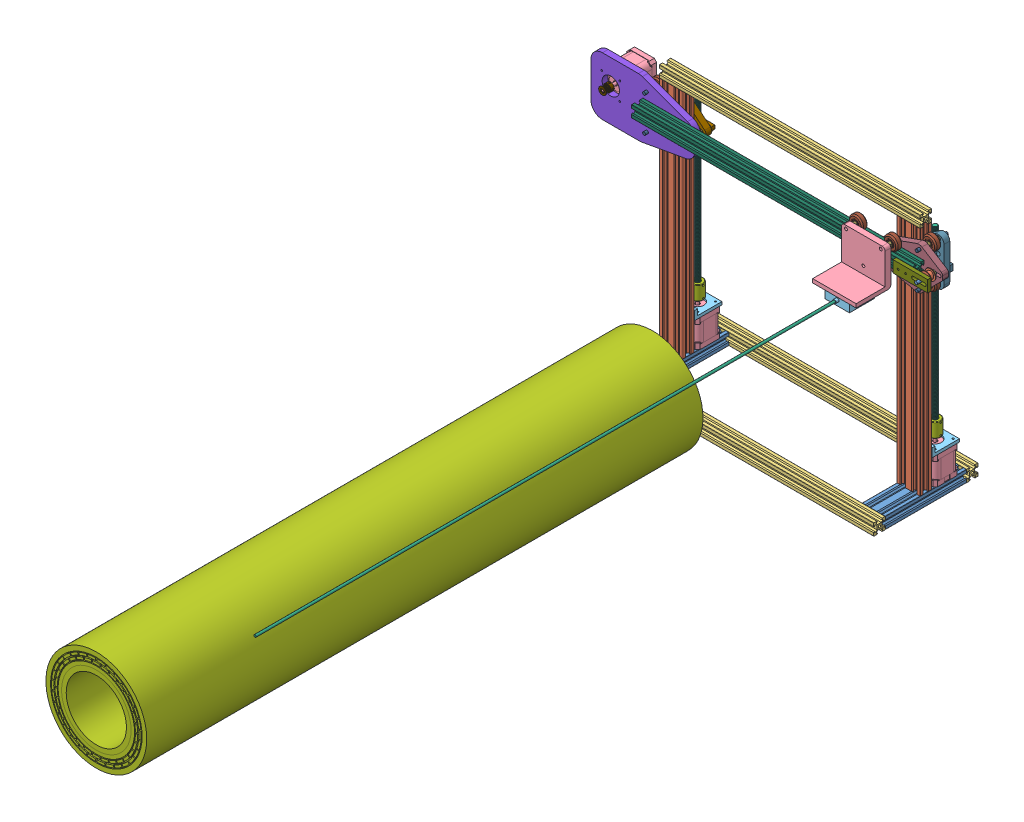
SolidWorks assembly Assembly_Design_1, configuration Default. Lengths in mm.
Overall size (607.25 440 1291.55).
72 component instances, 28 part files, 190 mates.
Components (placement in the parent):
- V_Slot_40x20_140mm-1: V_Slot_40x20_140mm [Default] at (9.5 10 -140) x (0 -1 0) z (0 0 1) size (20 40 140)
- V_Slot_40x20_400mm-1: V_Slot_40x20_400mm [Default] at (9.5 420 -70) x (0 0 -1) z (0 -1 0) size (20 40 400)
- V_Slot_20x20_450mm-1: V_Slot_20x20_450mm [Default] at (-0.5 430 -70) x (0 0 -1) z (1 0 0) size (20 20 450)
- V_Slot_40x20_400mm-2: V_Slot_40x20_400mm [Default] at (419.5 20 -70) x (0 0 1) z (0 1 0) size (20 40 400)
- V_Slot_40x20_140mm-2: V_Slot_40x20_140mm [Default] at (439.5 10 -140) x (0 1 0) z (0 0 1) size (20 40 140)
- V_Slot_20x20_450mm-2: V_Slot_20x20_450mm [Default] at (449.5 10 10) x (0 0 1) z (-1 0 0) size (20 20 450)
- V_Slot_20x20_450mm-3: V_Slot_20x20_450mm [Default] at (-0.5 10 -150) x (0 0 -1) z (1 0 0) size (20 20 450)
- Stepper_Motor_17HS19-2004S1-1: Stepper_Motor_17HS19-2004S1 [Predeterminado] at (19.5 44 -106) x (1 0 0) z (0 1 0) size (42 42 72)
- stepper_motor_mounting_bracket-1: stepper_motor_mounting_bracket [Default] at (19.5 68 -106) x (-1 0 0) z (0 1 0) size (42 47 15)
- Stepper_Motor_17HS19-2004S1-2: Stepper_Motor_17HS19-2004S1 [Predeterminado] at (429.5 44 -106) x (-1 0 0) z (0 1 0) size (42 42 72)
- stepper_motor_mounting_bracket-2: stepper_motor_mounting_bracket [Default] at (429.5 68 -106) x (-1 0 0) z (0 1 0) size (42 47 15)
- LeadScrew 8mm x 2mmPitch-1: LeadScrew 8mm x 2mmPitch [Default] at (429.5 92 -106) x (0.998698 0 -0.051019) z (0 -1 0) size (9.24 8.22 303.06)
- Coupling_Shaft_5x8-1: Coupling_Shaft_5x8 [Default] at (429.5 79.5 -106) x (0.999828 0 -0.01857) z (0.01857 0 0.999828) size (19 25 19)
- LeadScrew 8mm x 2mmPitch-2: LeadScrew 8mm x 2mmPitch [Default] at (19.5 92 -106) x (1 0 0) z (0 -1 0) size (9.24 8.22 303.06)
- Coupling_Shaft_5x8-2: Coupling_Shaft_5x8 [Default] at (19.5 79.5 -106) x (0.999319 0 -0.036886) z (0.036886 0 0.999319) size (19 25 19)
- leftbeam_wheel_mount_front-2: leftbeam_wheel_mount_front [Default] at (-107.5 320 -58.8) x (1 0 0) z (0 -1 0) size (180 10 100)
- Stepper_Motor_17HS19-2004S1-4: Stepper_Motor_17HS19-2004S1 [Predeterminado] at (-73 377.5 -82.8) size (42 42 72)
- leftbeam_wheel_mount_back-2: leftbeam_wheel_mount_back [Default] at (-21 326.9634 -91) x (1 0 0) z (0 -1 0) size (80 40 83.06)
- Wheel_mount_rod_for_brackets-1: Wheel_mount_rod_for_brackets [Default] at (-10.7 400 -96) x (-0.970108 -0.242673 0) z (-0.242673 0.970108 0) size (5 52.2 5)
- Wheel_mount_rod_for_brackets-2: Wheel_mount_rod_for_brackets [Default] at (-10.7 340 -96) x (-0.232708 0.972547 0) z (0.972547 0.232708 0) size (5 52.2 5)
- Wheel_mount_rod_for_brackets-3: Wheel_mount_rod_for_brackets [Default] at (49.8 355 -96) x (-0.732499 0.680769 0) z (0.680769 0.732499 0) size (5 52.2 5)
- V_Slot_Wheel_OD24xID5-1: V_Slot_Wheel_OD24xID5 [Default] at (-10.7 400 -69.9) x (0.993327 -0.115336 0) z (0 0 1) size (24 24 10.2)
- M5 Hex nut-1: M5 Hex nut [Default] at (-10.7 400 -61.8) x (0.939693 -0.34202 0) z (0.34202 0.939693 0) size (9.01 6.7 7.8)
- M5 Hex nut-2: M5 Hex nut [Default] at (-10.7 400 -78) x (0.939693 -0.34202 0) z (-0.34202 -0.939693 0) size (9.01 6.7 7.8)
- M5 Hex nut-3: M5 Hex nut [Default] at (-10.7 340 -61.8) x (0 -1 0) z (1 0 0) size (9.01 6.7 7.8)
- M5 Hex nut-4: M5 Hex nut [Default] at (-10.7 340 -78) x (0 -1 0) z (1 0 0) size (9.01 6.7 7.8)
- V_Slot_Wheel_OD24xID5-2: V_Slot_Wheel_OD24xID5 [Default] at (-10.7 340 -69.9) x (0.998331 -0.057756 0) z (0 0 1) size (24 24 10.2)
- M5 Hex nut-5: M5 Hex nut [Default] at (49.8 355 -78) x (0.866025 -0.5 0) z (-0.5 -0.866025 0) size (9.01 6.7 7.8)
- M5 Hex nut-6: M5 Hex nut [Default] at (49.8 355 -61.8) x (0.866025 -0.5 0) z (0.5 0.866025 0) size (9.01 6.7 7.8)
- V_Slot_Wheel_OD24xID5-3: V_Slot_Wheel_OD24xID5 [Default] at (49.8 355 -69.9) x (0.999874 0.01588 0) z (0 0 1) size (24 24 10.2)
- rightbeam_wheel_mount_front-1: rightbeam_wheel_mount_front [Default] at (499.75 372.8501 -58.8) size (110 73.04 10)
- rightbeam_wheels_mount _back-1: rightbeam_wheels_mount _back [Default] at (469.75 377.5 -91) size (80.5 81.06 40)
- Wheel_mount_rod_for_brackets-4: Wheel_mount_rod_for_brackets [Default] at (459.75 400 -96) x (0.11149 -0.993766 0) z (-0.993766 -0.11149 0) size (5 52.2 5)
- Wheel_mount_rod_for_brackets-5: Wheel_mount_rod_for_brackets [Default] at (399.25 355 -96) x (-0.923728 -0.383049 0) z (-0.383049 0.923728 0) size (5 52.2 5)
- Wheel_mount_rod_for_brackets-6: Wheel_mount_rod_for_brackets [Default] at (459.75 340 -96) x (-0.923728 -0.383049 0) z (-0.383049 0.923728 0) size (5 52.2 5)
- M5 Hex nut-7: M5 Hex nut [Default] at (459.75 340 -78) x (0.965926 -0.258819 0) z (-0.258819 -0.965926 0) size (9.01 6.7 7.8)
- M5 Hex nut-8: M5 Hex nut [Default] at (459.75 340 -61.8) x (0.965926 -0.258819 0) z (-0.258819 -0.965926 0) size (9.01 6.7 7.8)
- M5 Hex nut-9: M5 Hex nut [Default] at (399.25 355 -61.8) x (0.941742 0.336336 0) z (0.336336 -0.941742 0) size (9.01 6.7 7.8)
- M5 Hex nut-10: M5 Hex nut [Default] at (399.25 355 -78) x (0.941742 0.336336 0) z (0.336336 -0.941742 0) size (9.01 6.7 7.8)
- M5 Hex nut-11: M5 Hex nut [Default] at (459.75 400 -78) x (0.941742 0.336336 0) z (-0.336336 0.941742 0) size (9.01 6.7 7.8)
- M5 Hex nut-12: M5 Hex nut [Default] at (459.75 400 -61.8) x (0.941742 0.336336 0) z (0.336336 -0.941742 0) size (9.01 6.7 7.8)
- V_Slot_Wheel_OD24xID5-4: V_Slot_Wheel_OD24xID5 [Default] at (459.75 400 -69.9) x (0.615703 0.787979 0) z (0 0 1) size (24 24 10.2)
- V_Slot_Wheel_OD24xID5-5: V_Slot_Wheel_OD24xID5 [Default] at (459.75 340 -69.9) x (0.637684 0.770298 0) z (0 0 1) size (24 24 10.2)
- V_Slot_Wheel_OD24xID5-6: V_Slot_Wheel_OD24xID5 [Default] at (399.25 355 -69.9) x (0.99333 -0.115309 0) z (0 0 1) size (24 24 10.2)
- V_Slot_20x20_485-1: V_Slot_20x20_485 [Default] at (467.75 377.5 -38.8) x (0 0 1) z (-1 0 0) size (20 20 485)
- right_pulley_wheel_mount-1: right_pulley_wheel_mount [Default] at (439.75 367.5 -28.8) size (60 20 6)
- LeadScrew Nut 8mm x 2mmPitch-1: LeadScrew Nut 8mm x 2mmPitch [Default] at (429.5 334.9341 -106) x (-1 0 0) z (0 -1 0) size (22 22 16.05)
- LeadScrew Nut 8mm x 2mmPitch-2: LeadScrew Nut 8mm x 2mmPitch [Default] at (19.5 336.9634 -106) x (-1 0 0) z (0 -1 0) size (22 22 16.05)
- 16 teeth pulley GT2 6mm ASSEMBLY PART-1: 16 teeth pulley GT2 6mm ASSEMBLY PART [По умолчанию] at (-73.2117 377.9085 -27.2) x (-0.994801 0.101836 0) z (0 0 -1) size (13.17 13.17 14.1)
- 5x46mm_rod-1: 5x46mm_rod [Default] at (484.75 377.5 -17.8) x (0.599612 0.800291 0) z (-0.800291 0.599612 0) size (5 46 5)
- POWGE 2GT idler 20T B5-1: POWGE 2GT idler 20T B5 [Default] at (484.75 377.5 -38.8) x (0 0 1) z (0.346507 -0.938047 0) size (9 18 18)
- M5 Hex nut_5.5mm-1: M5 Hex nut_5.5mm [Default] at (484.75 377.5 -31.55) x (1 0 0) z (0 1 0) size (9.01 6.2 7.8)
- M5 Hex nut_5.5mm-2: M5 Hex nut_5.5mm [Default] at (484.75 377.5 -46.05) x (1 0 0) z (0 1 0) size (9.01 6.2 7.8)
- centre_laser_mount-1: centre_laser_mount [Default] at (393.9449 375.92 -27.7) x (1 0 0) z (0 -1 0) size (75 60 65)
- V_Slot_Wheel_OD24xID5-7: V_Slot_Wheel_OD24xID5 [Default] at (423.9449 397.92 -38.8) x (0.900063 0.43576 0) z (0 0 -1) size (24 24 10.2)
- V_Slot_Wheel_OD24xID5-8: V_Slot_Wheel_OD24xID5 [Default] at (363.9449 397.92 -38.8) x (0.900063 0.43576 0) z (0 0 -1) size (24 24 10.2)
- V_Slot_Wheel_OD24xID5-9: V_Slot_Wheel_OD24xID5 [Default] at (393.9449 357.92 -38.8) x (0.900063 0.43576 0) z (0 0 -1) size (24 24 10.2)
- M5 Hex nut-13: M5 Hex nut [Default] at (363.9449 397.92 -30.7) x (0 -1 0) z (1 0 0) size (9.01 6.7 7.8)
- M5 Hex nut-14: M5 Hex nut [Default] at (393.9449 357.92 -30.7) x (0 -1 0) z (1 0 0) size (9.01 6.7 7.8)
- M5 Hex nut-15: M5 Hex nut [Default] at (423.9449 397.92 -30.7) x (0 1 0) z (1 0 0) size (9.01 6.7 7.8)
- heavy hex flange screw_am-2: heavy hex flange screw_am [PreviewCfg] at (393.9449 357.92 -59) x (0 0 1) z (0.383049 -0.923728 0) size (75.1 32.8 32.8) (hidden)
- heavy hex flange screw_am-3: heavy hex flange screw_am [PreviewCfg] at (423.9449 397.92 -59) x (0 0 1) z (0.383049 -0.923728 0) size (75.1 32.8 32.8) (hidden)
- heavy hex flange screw_am-4: heavy hex flange screw_am [PreviewCfg] at (363.9449 397.92 -59) x (0 0 1) z (0.383049 -0.923728 0) size (75.1 32.8 32.8) (hidden)
- flat washer regular_am-1: flat washer regular_am [PreviewCfg] at (393.9449 357.92 -17.7) x (0 0 -1) z (0.380789 -0.924662 0) size (6.4 90 90) (hidden)
- flat washer regular_am-2: flat washer regular_am [PreviewCfg] at (423.9449 397.92 -17.7) x (0 0 -1) z (0.383049 -0.923728 0) size (6.4 90 90) (hidden)
- flat washer regular_am-3: flat washer regular_am [PreviewCfg] at (363.9449 397.92 -17.7) x (0 0 -1) z (0.383049 -0.923728 0) size (6.4 90 90) (hidden)
- hex flange nut_am-1: hex flange nut_am [PreviewCfg] at (423.9449 397.92 11.2298) x (0.923728 0.383049 0) z (0 0 1) size (42.8 42.8 22.53) (hidden)
- hex flange nut_am-2: hex flange nut_am [PreviewCfg] at (393.9449 357.92 11.2298) x (0.923728 0.383049 0) z (0 0 1) size (42.8 42.8 22.53) (hidden)
- hex flange nut_am-3: hex flange nut_am [PreviewCfg] at (363.9449 397.92 11.2298) x (0.923728 0.383049 0) z (0 0 1) size (42.8 42.8 22.53) (hidden)
- SEN0366_DFRobot_makeshift-1: SEN0366_DFRobot_makeshift [Default] at (372.9449 320.42 -15.7) x (0 0 1) z (-1 0 0) size (48 18 42)
- 4mm_laser_light_model-1: 4mm_laser_light_model [Default] at (393.9449 329.42 32.3) x (-0.923728 -0.383049 0) z (-0.383049 0.923728 0) size (4 1000 4)
- pipe-1: pipe [Default] at (219.3922 94.1141 1131.5467) size (174 174 960)
Mates (geometry in assembly coordinates):
- Coincident5: coincident: point of V_Slot_40x20_140mm-1
- Parallel1: parallel anti-aligned: plane of V_Slot_40x20_140mm-1 through (9.5 0 0) normal (0 -1 0)
- Parallel2: parallel aligned: plane of V_Slot_40x20_140mm-1 through (39.5 10 0) normal (1 0 0)
- Coincident12: coincident anti-aligned: plane of V_Slot_40x20_140mm-1 through (9.5 20 0) normal (0 1 0); plane of V_Slot_40x20_400mm-1 through (9.5 20 -70) normal (0 -1 0)
- Parallel5: parallel aligned: plane of V_Slot_40x20_140mm-1 through (-0.5 10 0) normal (-1 0 0); plane of V_Slot_40x20_400mm-1 through (-0.5 20 -70) normal (-1 0 0)
- Coincident15: coincident aligned: plane of V_Slot_40x20_140mm-1 through (-0.5 10 0) normal (-1 0 0); plane of V_Slot_40x20_400mm-1 through (-0.5 20 -70) normal (-1 0 0)
- Distance2: distance = 60 mm aligned: plane of V_Slot_40x20_400mm-1 through (9.5 20 -80) normal (0 0 -1); plane of V_Slot_40x20_140mm-1 through (9.5 10 -140) normal (0 0 -1)
- Coincident17: coincident anti-aligned: plane of V_Slot_40x20_400mm-1 through (9.5 420 -70) normal (0 1 0); plane of V_Slot_20x20_450mm-1 through (449.5 420 -65.42) normal (0 -1 0)
- Parallel6: parallel anti-aligned: plane of V_Slot_40x20_400mm-1 through (-0.5 20 -70) normal (-1 0 0); plane of V_Slot_20x20_450mm-1 through (449.5 439.5 -79.5) normal (1 0 0)
- Coincident19: coincident aligned: plane of V_Slot_40x20_400mm-1 through (-0.5 20 -70) normal (-1 0 0); plane of V_Slot_20x20_450mm-1 through (-0.5 439.5 -79.5) normal (-1 0 0)
- Coincident20: coincident aligned: plane of V_Slot_40x20_400mm-1 through (9.5 20 -80) normal (0 0 -1); plane of V_Slot_20x20_450mm-1 through (449.5 420.5 -80) normal (0 0 -1)
- Coincident21: coincident anti-aligned: plane of V_Slot_20x20_450mm-1 through (449.5 420 -65.42) normal (0 -1 0); plane of V_Slot_40x20_400mm-2 through (419.5 420 -70) normal (0 1 0)
- Parallel7: parallel anti-aligned: plane of V_Slot_20x20_450mm-1 through (449.5 439.5 -79.5) normal (1 0 0); plane of V_Slot_40x20_400mm-2 through (409.5 420 -70) normal (-1 0 0)
- Coincident23: coincident aligned: plane of V_Slot_20x20_450mm-1 through (449.5 439.5 -79.5) normal (1 0 0); plane of V_Slot_40x20_400mm-2 through (449.5 420 -70) normal (1 0 0)
- Coincident24: coincident aligned: plane of V_Slot_20x20_450mm-1 through (449.5 420.5 -60) normal (0 0 1); plane of V_Slot_40x20_400mm-2 through (419.5 420 -60) normal (0 0 1)
- Coincident25: coincident anti-aligned: plane of V_Slot_40x20_400mm-2 through (419.5 20 -70) normal (0 -1 0); plane of V_Slot_40x20_140mm-2 through (439.5 20 0) normal (0 1 0)
- Coincident26: coincident aligned: plane of V_Slot_40x20_400mm-2 through (409.5 420 -70) normal (-1 0 0); plane of V_Slot_40x20_140mm-2 through (409.5 10 0) normal (-1 0 0)
- Distance3: distance = 60 mm aligned: plane of V_Slot_40x20_400mm-2 through (419.5 420 -80) normal (0 0 -1); plane of V_Slot_40x20_140mm-2 through (439.5 10 -140) normal (0 0 -1)
- Coincident28: coincident anti-aligned: plane of V_Slot_40x20_140mm-2 through (439.5 10 0) normal (0 0 1); plane of V_Slot_20x20_450mm-2 through (-0.5 19.5 0) normal (0 0 -1)
- Coincident29: coincident aligned: plane of V_Slot_40x20_140mm-1 through (-0.5 10 0) normal (-1 0 0); plane of V_Slot_20x20_450mm-2 through (-0.5 19.5 19.5) normal (-1 0 0)
- Coincident30: coincident aligned: plane of V_Slot_40x20_140mm-1 through (9.5 20 0) normal (0 1 0); plane of V_Slot_20x20_450mm-2 through (-0.5 20 5.42) normal (0 1 0)
- Coincident31: coincident anti-aligned: plane of V_Slot_40x20_140mm-2 through (439.5 10 -140) normal (0 0 -1); plane of V_Slot_20x20_450mm-3 through (449.5 19.5 -140) normal (0 0 1)
- Coincident32: coincident aligned: plane of V_Slot_40x20_140mm-2 through (449.5 10 0) normal (1 0 0); plane of V_Slot_20x20_450mm-3 through (449.5 19.5 -159.5) normal (1 0 0)
- Coincident33: coincident aligned: plane of V_Slot_40x20_140mm-2 through (439.5 20 0) normal (0 1 0); plane of V_Slot_20x20_450mm-3 through (449.5 20 -145.42) normal (0 1 0)
- Coincident34: coincident anti-aligned: plane of V_Slot_40x20_140mm-1 through (9.5 20 0) normal (0 1 0); plane of Stepper_Motor_17HS19-2004S1-1 through (19.5 20 -106) normal (0 -1 0)
- Parallel8: parallel aligned: plane of V_Slot_40x20_140mm-1 through (-0.5 10 0) normal (-1 0 0); plane of Stepper_Motor_17HS19-2004S1-1 through (-1.5 68 -123) normal (-1 0 0)
- Coincident36: coincident anti-aligned: plane of Stepper_Motor_17HS19-2004S1-1 through (19.5 68 -106) normal (0 1 0); plane of stepper_motor_mounting_bracket-1 through (19.5 68 -106) normal (0 -1 0)
- Concentric1: concentric aligned: circle of Stepper_Motor_17HS19-2004S1-1; circle of stepper_motor_mounting_bracket-1
- Coincident38: coincident anti-aligned: plane of V_Slot_40x20_400mm-1 through (9.5 20 -80) normal (0 0 -1); plane of stepper_motor_mounting_bracket-1 through (40.5 73 -80) normal (0 0 1)
- Distance4: distance = 1 mm aligned: plane of stepper_motor_mounting_bracket-1 through (40.5 73 -85) normal (1 0 0); plane of V_Slot_40x20_400mm-1 through (39.5 20 -70) normal (1 0 0)
- Coincident40: coincident anti-aligned: plane of V_Slot_40x20_140mm-2 through (439.5 20 0) normal (0 1 0); plane of Stepper_Motor_17HS19-2004S1-2 through (429.5 20 -106) normal (0 -1 0)
- Parallel9: parallel anti-aligned: plane of V_Slot_40x20_400mm-2 through (419.5 420 -80) normal (0 0 -1); plane of Stepper_Motor_17HS19-2004S1-2 through (412.5 68 -85) normal (0 0 1)
- Coincident42: coincident anti-aligned: plane of Stepper_Motor_17HS19-2004S1-2 through (429.5 68 -106) normal (0 1 0); plane of stepper_motor_mounting_bracket-2 through (429.5 68 -106) normal (0 -1 0)
- Concentric2: concentric aligned: circle of Stepper_Motor_17HS19-2004S1-2; circle of stepper_motor_mounting_bracket-2
- Coincident44: coincident anti-aligned: plane of V_Slot_40x20_400mm-2 through (419.5 420 -80) normal (0 0 -1); plane of stepper_motor_mounting_bracket-2 through (450.5 73 -80) normal (0 0 1)
- Distance5: distance = 1 mm aligned: plane of stepper_motor_mounting_bracket-2 through (450.5 73 -85) normal (1 0 0); plane of V_Slot_40x20_400mm-2 through (449.5 420 -70) normal (1 0 0)
- Concentric3: concentric aligned: cylinder of Stepper_Motor_17HS19-2004S1-2 through (429.5 92 -106) axis (0 -1 0) radius 2.5; cylinder of Coupling_Shaft_5x8-1 through (429.5 104.5 -106) axis (0 -1 0) radius 2.5
- Coincident46: coincident aligned: plane of Stepper_Motor_17HS19-2004S1-2 through (429.5 92 -106) normal (0 1 0); plane of Coupling_Shaft_5x8-1 through (429.5 92 -106) normal (0 1 0)
- Lock1: lock: unknown of stepper_motor_mounting_bracket-2; unknown of Coupling_Shaft_5x8-1
- Concentric4: concentric anti-aligned: cylinder of LeadScrew 8mm x 2mmPitch-1 through (429.5 392 -106) axis (0 -1 0) radius 4; cylinder of Coupling_Shaft_5x8-1 through (429.5 92 -106) axis (0 1 0) radius 4
- Coincident47: coincident anti-aligned: plane of LeadScrew 8mm x 2mmPitch-1 through (429.5 92 -106) normal (0 -1 0); plane of Coupling_Shaft_5x8-1 through (429.5 92 -106) normal (0 1 0)
- Lock2: lock: unknown of LeadScrew 8mm x 2mmPitch-1; unknown of Coupling_Shaft_5x8-1
- Concentric5: concentric aligned: cylinder of Stepper_Motor_17HS19-2004S1-1 through (19.5 92 -106) axis (0 -1 0) radius 2.5; cylinder of Coupling_Shaft_5x8-2 through (19.5 104.5 -106) axis (0 -1 0) radius 2.5
- Coincident48: coincident aligned: plane of Stepper_Motor_17HS19-2004S1-1 through (19.5 92 -106) normal (0 1 0); plane of Coupling_Shaft_5x8-2 through (19.5 92 -106) normal (0 1 0)
- Lock3: lock: unknown of stepper_motor_mounting_bracket-1; unknown of Coupling_Shaft_5x8-2
- Coincident49: coincident anti-aligned: plane of LeadScrew 8mm x 2mmPitch-2 through (19.5 92 -106) normal (0 -1 0); plane of Coupling_Shaft_5x8-2 through (19.5 92 -106) normal (0 1 0)
- Concentric6: concentric anti-aligned: cylinder of LeadScrew 8mm x 2mmPitch-2 through (19.5 392 -106) axis (0 -1 0) radius 4; cylinder of Coupling_Shaft_5x8-2 through (19.5 92 -106) axis (0 1 0) radius 4
- Lock4: lock: unknown of LeadScrew 8mm x 2mmPitch-2; unknown of Coupling_Shaft_5x8-2
- Parallel15: parallel anti-aligned: plane of V_Slot_40x20_400mm-1 through (9.5 20 -60) normal (0 0 1); plane of leftbeam_wheel_mount_front-2 through (-107.5 320 -58.8) normal (0 0 -1)
- Concentric13: concentric aligned: cylinder of leftbeam_wheel_mount_front-2 through (-73 377.5 -48.8) axis (0 0 -1) radius 15; cylinder of Stepper_Motor_17HS19-2004S1-4 through (-73 377.5 -34.8) axis (0 0 -1) radius 2.5
- Parallel16: parallel aligned: plane of leftbeam_wheel_mount_front-2 through (-107.5 320 -48.8) normal (-1 0 0); plane of Stepper_Motor_17HS19-2004S1-4 through (-94 377.5 -106.802) normal (-1 0 0)
- Concentric14: concentric anti-aligned: cylinder of LeadScrew 8mm x 2mmPitch-2 through (19.5 392 -106) axis (0 -1 0) radius 4; cylinder of leftbeam_wheel_mount_back-2 through (19.5 326.9634 -106) axis (0 1 0) radius 5.25
- Concentric15: concentric aligned: circle of leftbeam_wheel_mount_front-2; circle of leftbeam_wheel_mount_back-2
- Concentric16: concentric anti-aligned: cylinder of Wheel_mount_rod_for_brackets-1 through (-10.7 400 -43.8) axis (0 0 -1) radius 2.5; cylinder of V_Slot_Wheel_OD24xID5-1 through (-10.7 400 -75) axis (0 0 1) radius 2.5
- Concentric17: concentric aligned: circle of leftbeam_wheel_mount_front-2; circle of leftbeam_wheel_mount_back-2
- Concentric18: concentric anti-aligned: cylinder of Wheel_mount_rod_for_brackets-1 through (-10.7 400 -43.8) axis (0 0 -1) radius 2.5; circle of M5 Hex nut-1
- Coincident67: coincident anti-aligned: plane of V_Slot_Wheel_OD24xID5-1 through (-10.7 400 -64.8) normal (0 0 1); plane of M5 Hex nut-1 through (-10.7 400 -64.8) normal (0 0 -1)
- Concentric20: concentric anti-aligned: cylinder of Wheel_mount_rod_for_brackets-1 through (-10.7 400 -43.8) axis (0 0 -1) radius 2.5; circle of M5 Hex nut-2
- Coincident69: coincident anti-aligned: plane of V_Slot_Wheel_OD24xID5-1 through (-10.7 400 -75) normal (0 0 -1); plane of M5 Hex nut-2 through (-10.7 400 -75) normal (0 0 1)
- Coincident70: coincident anti-aligned: plane of leftbeam_wheel_mount_front-2 through (-107.5 320 -58.8) normal (0 0 -1); plane of M5 Hex nut-1 through (-10.7 400 -58.8) normal (0 0 1)
- Parallel17: parallel aligned: plane of M5 Hex nut-1 through (-11.482 404.4349 -64.8) normal (0.34202 0.939693 0); plane of M5 Hex nut-2 through (-7.2502 402.8947 -75) normal (0.34202 0.939693 0)
- Parallel18: parallel aligned: plane of leftbeam_wheel_mount_front-2 through (-65.3464 435.8159 -48.8) normal (0.34202 0.939693 0); plane of M5 Hex nut-2 through (-7.2502 402.8947 -75) normal (0.34202 0.939693 0)
- Coincident73: coincident anti-aligned: plane of leftbeam_wheel_mount_back-2 through (53 353.7309 -81) normal (0 0 1); plane of M5 Hex nut-2 through (-10.7 400 -81) normal (0 0 -1)
- Concentric21: concentric aligned: circle of leftbeam_wheel_mount_front-2; circle of Wheel_mount_rod_for_brackets-2
- Concentric22: concentric aligned: circle of leftbeam_wheel_mount_front-2; circle of Wheel_mount_rod_for_brackets-3
- Concentric23: concentric aligned: circle of leftbeam_wheel_mount_front-2; circle of Wheel_mount_rod_for_brackets-1
- Concentric24: concentric anti-aligned: cylinder of Wheel_mount_rod_for_brackets-2 through (-10.7 340 -43.8) axis (0 0 -1) radius 2.5; cylinder of V_Slot_Wheel_OD24xID5-2 through (-10.7 340 -75) axis (0 0 1) radius 2.5
- Concentric26: concentric aligned: cone of leftbeam_wheel_mount_back-2; cone of M5 Hex nut-4 through (-10.7 340 -80.84) axis (0 0 1)
- Coincident78: coincident anti-aligned: plane of leftbeam_wheel_mount_back-2 through (53 353.7309 -81) normal (0 0 1); plane of M5 Hex nut-4 through (-10.7 340 -81) normal (0 0 -1)
- Coincident79: coincident anti-aligned: plane of M5 Hex nut-4 through (-10.7 340 -75) normal (0 0 1); plane of V_Slot_Wheel_OD24xID5-2 through (-10.7 340 -75) normal (0 0 -1)
- Concentric27: concentric anti-aligned: circle of leftbeam_wheel_mount_front-2; circle of M5 Hex nut-3
- Coincident81: coincident anti-aligned: plane of leftbeam_wheel_mount_front-2 through (-107.5 320 -58.8) normal (0 0 -1); plane of M5 Hex nut-3 through (-10.7 340 -58.8) normal (0 0 1)
- Parallel19: parallel aligned: plane of M5 Hex nut-3 through (-6.8 342.2517 -64.8) normal (1 0 0); plane of M5 Hex nut-4 through (-6.8 342.2517 -81) normal (1 0 0)
- Parallel20: parallel anti-aligned: plane of leftbeam_wheel_mount_back-2 through (-21 332.9634 -81) normal (-1 0 0); plane of M5 Hex nut-4 through (-6.8 342.2517 -81) normal (1 0 0)
- Concentric28: concentric anti-aligned: cylinder of Wheel_mount_rod_for_brackets-3 through (49.8 355 -43.8) axis (0 0 -1) radius 2.5; cylinder of V_Slot_Wheel_OD24xID5-3 through (49.8 355 -75) axis (0 0 1) radius 2.5
- Concentric29: concentric anti-aligned: cylinder of Wheel_mount_rod_for_brackets-3 through (49.8 355 -43.8) axis (0 0 -1) radius 2.5; circle of M5 Hex nut-5
- Coincident85: coincident anti-aligned: plane of M5 Hex nut-5 through (49.8 355 -75) normal (0 0 1); plane of V_Slot_Wheel_OD24xID5-3 through (49.8 355 -75) normal (0 0 -1)
- Coincident86: coincident anti-aligned: plane of leftbeam_wheel_mount_back-2 through (53 353.7309 -81) normal (0 0 1); plane of M5 Hex nut-5 through (49.8 355 -81) normal (0 0 -1)
- Concentric30: concentric anti-aligned: circle of leftbeam_wheel_mount_front-2; circle of M5 Hex nut-6
- Coincident87: coincident anti-aligned: plane of leftbeam_wheel_mount_front-2 through (-107.5 320 -58.8) normal (0 0 -1); plane of M5 Hex nut-6 through (49.8 355 -58.8) normal (0 0 1)
- Parallel21: parallel aligned: plane of M5 Hex nut-5 through (53.7 352.7483 -75) normal (1 0 0); plane of M5 Hex nut-6 through (53.7 357.2517 -64.8) normal (1 0 0)
- Parallel22: parallel aligned: plane of leftbeam_wheel_mount_front-2 through (72.5 320 -48.8) normal (1 0 0); plane of M5 Hex nut-6 through (53.7 357.2517 -64.8) normal (1 0 0)
- Distance6: distance = 5 mm aligned: plane of Wheel_mount_rod_for_brackets-1 through (-10.7 400 -96) normal (0 0 -1); plane of leftbeam_wheel_mount_back-2 through (53 353.7309 -91) normal (0 0 -1)
- Distance8: distance = 5 mm aligned: plane of Wheel_mount_rod_for_brackets-2 through (-10.7 340 -96) normal (0 0 -1); plane of leftbeam_wheel_mount_back-2 through (53 353.7309 -91) normal (0 0 -1)
- Distance9: distance = 5 mm aligned: plane of Wheel_mount_rod_for_brackets-3 through (49.8 355 -96) normal (0 0 -1); plane of leftbeam_wheel_mount_back-2 through (53 353.7309 -91) normal (0 0 -1)
- Coincident90: coincident aligned: plane of leftbeam_wheel_mount_front-2 through (-107.5 320 -48.8) normal (0 0 1); plane of rightbeam_wheel_mount_front-1 through (458.5548 396.8046 -48.8) normal (0 0 1)
- Concentric31: concentric anti-aligned: cylinder of LeadScrew 8mm x 2mmPitch-1 through (429.5 392 -106) axis (0 -1 0) radius 4; cylinder of rightbeam_wheels_mount _back-1 through (429.5 324.9341 -106) axis (0 1 0) radius 5.25
- Parallel25: parallel anti-aligned: plane of rightbeam_wheel_mount_front-1 through (458.5548 396.8046 -58.8) normal (0 0 -1); plane of rightbeam_wheels_mount _back-1 through (408.25 332.1629 -81) normal (0 0 1)
- Concentric32: concentric aligned: cylinder of rightbeam_wheel_mount_front-1 through (459.75 400 -48.8) axis (0 0 -1) radius 2.5; cylinder of rightbeam_wheels_mount _back-1 through (459.75 400 -81) axis (0 0 -1) radius 2.5
- Concentric33: concentric aligned: cylinder of rightbeam_wheel_mount_front-1 through (459.75 340 -48.8) axis (0 0 -1) radius 2.5; cylinder of rightbeam_wheels_mount _back-1 through (459.75 340 -81) axis (0 0 -1) radius 2.5
- Concentric34: concentric aligned: cylinder of rightbeam_wheel_mount_front-1 through (399.25 355 -48.8) axis (0 0 -1) radius 2.5; cylinder of rightbeam_wheels_mount _back-1 through (399.25 355 -81) axis (0 0 -1) radius 2.5
- Concentric35: concentric aligned: circle of rightbeam_wheel_mount_front-1; circle of Wheel_mount_rod_for_brackets-4
- Distance10: distance = 5 mm aligned: plane of Wheel_mount_rod_for_brackets-4 through (459.75 400 -43.8) normal (0 0 1); plane of rightbeam_wheel_mount_front-1 through (458.5548 396.8046 -48.8) normal (0 0 1)
- Concentric36: concentric aligned: circle of rightbeam_wheel_mount_front-1; circle of Wheel_mount_rod_for_brackets-6
- Distance11: distance = 5 mm aligned: plane of Wheel_mount_rod_for_brackets-6 through (459.75 340 -96) normal (0 0 -1); plane of rightbeam_wheels_mount _back-1 through (408.25 332.1629 -91) normal (0 0 -1)
- Concentric37: concentric aligned: circle of rightbeam_wheel_mount_front-1; circle of Wheel_mount_rod_for_brackets-5
- Distance12: distance = 5 mm aligned: plane of Wheel_mount_rod_for_brackets-5 through (399.25 355 -96) normal (0 0 -1); plane of rightbeam_wheels_mount _back-1 through (408.25 332.1629 -91) normal (0 0 -1)
- Concentric38: concentric anti-aligned: circle of rightbeam_wheel_mount_front-1; circle of M5 Hex nut-11
- Coincident99: coincident anti-aligned: plane of rightbeam_wheels_mount _back-1 through (408.25 332.1629 -81) normal (0 0 1); plane of M5 Hex nut-11 through (459.75 400 -81) normal (0 0 -1)
- Concentric39: concentric anti-aligned: cylinder of Wheel_mount_rod_for_brackets-4 through (459.75 400 -43.8) axis (0 0 -1) radius 2.5; cylinder of V_Slot_Wheel_OD24xID5-4 through (459.75 400 -75) axis (0 0 1) radius 2.5
- Coincident100: coincident anti-aligned: plane of M5 Hex nut-11 through (459.75 400 -75) normal (0 0 1); plane of V_Slot_Wheel_OD24xID5-4 through (459.75 400 -75) normal (0 0 -1)
- Concentric40: concentric anti-aligned: circle of rightbeam_wheel_mount_front-1; circle of M5 Hex nut-12
- Coincident101: coincident anti-aligned: plane of rightbeam_wheel_mount_front-1 through (458.5548 396.8046 -58.8) normal (0 0 -1); plane of M5 Hex nut-12 through (459.75 400 -58.8) normal (0 0 1)
- Concentric41: concentric anti-aligned: circle of rightbeam_wheel_mount_front-1; circle of M5 Hex nut-7
- Coincident102: coincident anti-aligned: plane of rightbeam_wheels_mount _back-1 through (408.25 332.1629 -81) normal (0 0 1); plane of M5 Hex nut-7 through (459.75 340 -81) normal (0 0 -1)
- Concentric42: concentric anti-aligned: cylinder of Wheel_mount_rod_for_brackets-6 through (459.75 340 -43.8) axis (0 0 -1) radius 2.5; cylinder of V_Slot_Wheel_OD24xID5-5 through (459.75 340 -75) axis (0 0 1) radius 2.5
- Coincident103: coincident anti-aligned: plane of M5 Hex nut-7 through (459.75 340 -75) normal (0 0 1); plane of V_Slot_Wheel_OD24xID5-5 through (459.75 340 -75) normal (0 0 -1)
- Concentric43: concentric anti-aligned: circle of rightbeam_wheel_mount_front-1; circle of M5 Hex nut-8
- Coincident104: coincident anti-aligned: plane of rightbeam_wheel_mount_front-1 through (458.5548 396.8046 -58.8) normal (0 0 -1); plane of M5 Hex nut-8 through (459.75 340 -58.8) normal (0 0 1)
- Concentric44: concentric anti-aligned: circle of rightbeam_wheel_mount_front-1; circle of M5 Hex nut-10
- Coincident105: coincident anti-aligned: plane of rightbeam_wheels_mount _back-1 through (408.25 332.1629 -81) normal (0 0 1); plane of M5 Hex nut-10 through (399.25 355 -81) normal (0 0 -1)
- Concentric45: concentric anti-aligned: cylinder of Wheel_mount_rod_for_brackets-5 through (399.25 355 -43.8) axis (0 0 -1) radius 2.5; cylinder of V_Slot_Wheel_OD24xID5-6 through (399.25 355 -75) axis (0 0 1) radius 2.5
- Coincident106: coincident anti-aligned: plane of M5 Hex nut-10 through (399.25 355 -75) normal (0 0 1); plane of V_Slot_Wheel_OD24xID5-6 through (399.25 355 -75) normal (0 0 -1)
- Concentric46: concentric anti-aligned: circle of rightbeam_wheel_mount_front-1; circle of M5 Hex nut-9
- Coincident107: coincident anti-aligned: plane of rightbeam_wheel_mount_front-1 through (458.5548 396.8046 -58.8) normal (0 0 -1); plane of M5 Hex nut-9 through (399.25 355 -58.8) normal (0 0 1)
- Parallel26: parallel aligned: plane of M5 Hex nut-9 through (400.0588 359.4301 -58.8) normal (-0.336336 0.941742 0); plane of M5 Hex nut-10 through (400.0588 359.4301 -75) normal (-0.336336 0.941742 0)
- Parallel27: parallel aligned: plane of rightbeam_wheel_mount_front-1 through (455.1914 406.222 -48.8) normal (-0.336336 0.941742 0); plane of M5 Hex nut-9 through (400.0588 359.4301 -58.8) normal (-0.336336 0.941742 0)
- Parallel28: parallel aligned: plane of M5 Hex nut-11 through (456.3178 402.9155 -81) normal (-0.336336 0.941742 0); plane of M5 Hex nut-12 through (460.5588 404.4301 -58.8) normal (-0.336336 0.941742 0)
- Parallel29: parallel aligned: plane of rightbeam_wheel_mount_front-1 through (455.1914 406.222 -48.8) normal (-0.336336 0.941742 0); plane of M5 Hex nut-11 through (456.3178 402.9155 -81) normal (-0.336336 0.941742 0)
- Parallel30: parallel aligned: plane of M5 Hex nut-7 through (460.9155 335.6501 -75) normal (0.707107 -0.707107 0); plane of M5 Hex nut-8 through (460.9155 335.6501 -58.8) normal (0.707107 -0.707107 0)
- Parallel31: parallel aligned: plane of rightbeam_wheel_mount_front-1 through (463.5969 336.6969 -48.8) normal (0.707107 -0.707107 0); plane of M5 Hex nut-8 through (460.9155 335.6501 -58.8) normal (0.707107 -0.707107 0)
- Coincident114: coincident anti-aligned: plane of leftbeam_wheel_mount_front-2 through (-107.5 320 -48.8) normal (0 0 1); plane of V_Slot_20x20_485-1 through (-17.25 387 -48.8) normal (0 0 -1)
- Concentric47: concentric anti-aligned: circle of leftbeam_wheel_mount_front-2; circle of V_Slot_20x20_485-1
- Concentric48: concentric anti-aligned: circle of rightbeam_wheel_mount_front-1; circle of V_Slot_20x20_485-1
- Parallel32: parallel aligned: plane of leftbeam_wheel_mount_front-2 through (-107.5 320 -48.8) normal (0 0 1); plane of V_Slot_20x20_485-1 through (-17.25 387 -28.8) normal (0 0 1)
- Parallel33: parallel anti-aligned: plane of rightbeam_wheel_mount_front-1 through (458.5548 396.8046 -48.8) normal (0 0 1); plane of right_pulley_wheel_mount-1 through (439.75 367.5 -28.8) normal (0 0 -1)
- Parallel34: parallel aligned: plane of V_Slot_20x20_485-1 through (-17.25 387.5 -43.38) normal (0 1 0); plane of right_pulley_wheel_mount-1 through (439.75 387.5 -22.8) normal (0 1 0)
- Concentric49: concentric aligned: circle of rightbeam_wheel_mount_front-1; circle of right_pulley_wheel_mount-1
- Coincident125: coincident anti-aligned: plane of V_Slot_20x20_485-1 through (-17.25 387 -28.8) normal (0 0 1); plane of right_pulley_wheel_mount-1 through (439.75 367.5 -28.8) normal (0 0 -1)
- Concentric50: concentric aligned: cylinder of LeadScrew 8mm x 2mmPitch-1 through (429.5 392 -106) axis (0 -1 0) radius 4; cylinder of LeadScrew Nut 8mm x 2mmPitch-1 through (429.5 348.4341 -106) axis (0 -1 0) radius 4
- Coincident126: coincident anti-aligned: plane of rightbeam_wheels_mount _back-1 through (445.75 334.9341 -121) normal (0 1 0); plane of LeadScrew Nut 8mm x 2mmPitch-1 through (429.5 334.9341 -106) normal (0 -1 0)
- Concentric51: concentric anti-aligned: circle of rightbeam_wheels_mount _back-1; circle of LeadScrew Nut 8mm x 2mmPitch-1
- Concentric52: concentric anti-aligned: circle of rightbeam_wheels_mount _back-1; circle of LeadScrew Nut 8mm x 2mmPitch-1
- Concentric53: concentric aligned: cylinder of LeadScrew 8mm x 2mmPitch-2 through (19.5 392 -106) axis (0 -1 0) radius 4; cylinder of LeadScrew Nut 8mm x 2mmPitch-2 through (19.5 350.4634 -106) axis (0 -1 0) radius 4
- Coincident129: coincident anti-aligned: plane of leftbeam_wheel_mount_back-2 through (53 336.9634 -121) normal (0 1 0); plane of LeadScrew Nut 8mm x 2mmPitch-2 through (19.5 336.9634 -106) normal (0 -1 0)
- Concentric54: concentric aligned: circle of leftbeam_wheel_mount_back-2; circle of LeadScrew Nut 8mm x 2mmPitch-2
- Concentric55: concentric aligned: circle of leftbeam_wheel_mount_back-2; circle of LeadScrew Nut 8mm x 2mmPitch-2
- Parallel37: parallel anti-aligned: plane of right_pulley_wheel_mount-1 through (439.75 367.5 -22.8) normal (0 0 1); plane of 5x46mm_rod-1 through (484.75 377.5 -63.8) normal (0 0 -1)
- Tangent2: tangent anti-aligned: plane of right_pulley_wheel_mount-1 through (474.75 375 -22.8) normal (0 1 0); cylinder of 5x46mm_rod-1 through (484.75 377.5 -63.8) axis (0 0 1) radius 2.5
- Distance15: distance = 5 mm aligned: plane of 5x46mm_rod-1 through (484.75 377.5 -17.8) normal (0 0 1); plane of right_pulley_wheel_mount-1 through (439.75 367.5 -22.8) normal (0 0 1)
- Distance16: distance = 10 mm: cylinder of 5x46mm_rod-1 through (484.75 377.5 -63.8) axis (0 0 1) radius 2.5; cylinder of right_pulley_wheel_mount-1 through (474.75 377.5 -22.8) axis (0 0 -1) radius 2.5
- Concentric59: concentric aligned: cylinder of Stepper_Motor_17HS19-2004S1-4 through (-73 377.5 -34.8) axis (0 0 -1) radius 2.5; cylinder of 16 teeth pulley GT2 6mm ASSEMBLY PART-1 through (-73 377.5 -34.25) axis (0 0 -1) radius 2.5
- Distance17: distance = 0.425 mm: line of 16 teeth pulley GT2 6mm ASSEMBLY PART-1; line of V_Slot_20x20_485-1 through (-17.25 386.045 -41.925) axis (1 0 0)
- Lock5: lock: unknown of Stepper_Motor_17HS19-2004S1-4; unknown of 16 teeth pulley GT2 6mm ASSEMBLY PART-1
- Concentric61: concentric anti-aligned: cylinder of 5x46mm_rod-1 through (484.75 377.5 -63.8) axis (0 0 1) radius 2.5; cylinder of POWGE 2GT idler 20T B5-1 through (484.75 377.5 -36.55) axis (0 0 -1) radius 2.5
- Distance18: distance = 0.375 mm: plane of POWGE 2GT idler 20T B5-1 through (487.3618 370.4295 -35.3) normal (0 0 -1); line of V_Slot_20x20_485-1 through (-17.25 386.045 -35.675) axis (1 0 0)
- Concentric62: concentric anti-aligned: cylinder of 5x46mm_rod-1 through (484.75 377.5 -63.8) axis (0 0 1) radius 2.5; circle of M5 Hex nut_5.5mm-1
- Coincident139: coincident anti-aligned: plane of POWGE 2GT idler 20T B5-1 through (487.0889 371.1682 -34.3) normal (0 0 1); plane of M5 Hex nut_5.5mm-1 through (484.75 377.5 -34.3) normal (0 0 -1)
- Concentric63: concentric aligned: cylinder of 5x46mm_rod-1 through (484.75 377.5 -63.8) axis (0 0 1) radius 2.5; circle of M5 Hex nut_5.5mm-2
- Coincident140: coincident anti-aligned: plane of POWGE 2GT idler 20T B5-1 through (487.0889 371.1682 -43.3) normal (0 0 -1); plane of M5 Hex nut_5.5mm-2 through (484.75 377.5 -43.3) normal (0 0 1)
- Concentric64: concentric anti-aligned: circle of centre_laser_mount-1; circle of M5 Hex nut-13
- Coincident141: coincident anti-aligned: plane of centre_laser_mount-1 through (393.9449 375.92 -27.7) normal (0 0 -1); plane of M5 Hex nut-13 through (363.9449 397.92 -27.7) normal (0 0 1)
- Concentric65: concentric anti-aligned: circle of V_Slot_Wheel_OD24xID5-8; circle of M5 Hex nut-13
- Coincident142: coincident anti-aligned: plane of V_Slot_Wheel_OD24xID5-8 through (363.9449 397.92 -33.7) normal (0 0 1); plane of M5 Hex nut-13 through (363.9449 397.92 -33.7) normal (0 0 -1)
- Concentric66: concentric anti-aligned: circle of centre_laser_mount-1; circle of M5 Hex nut-15
- Coincident143: coincident anti-aligned: plane of centre_laser_mount-1 through (393.9449 375.92 -27.7) normal (0 0 -1); plane of M5 Hex nut-15 through (423.9449 397.92 -27.7) normal (0 0 1)
- Concentric67: concentric anti-aligned: circle of V_Slot_Wheel_OD24xID5-7; circle of M5 Hex nut-15
- Coincident144: coincident anti-aligned: plane of V_Slot_Wheel_OD24xID5-7 through (423.9449 397.92 -33.7) normal (0 0 1); plane of M5 Hex nut-15 through (423.9449 397.92 -33.7) normal (0 0 -1)
- Concentric68: concentric anti-aligned: circle of centre_laser_mount-1; circle of M5 Hex nut-14
- Coincident145: coincident anti-aligned: plane of centre_laser_mount-1 through (393.9449 375.92 -27.7) normal (0 0 -1); plane of M5 Hex nut-14 through (393.9449 357.92 -27.7) normal (0 0 1)
- Concentric69: concentric anti-aligned: circle of V_Slot_Wheel_OD24xID5-9; circle of M5 Hex nut-14
- Coincident146: coincident anti-aligned: plane of V_Slot_Wheel_OD24xID5-9 through (393.9449 357.92 -33.7) normal (0 0 1); plane of M5 Hex nut-14 through (393.9449 357.92 -33.7) normal (0 0 -1)
- Concentric70: concentric aligned: cylinder of V_Slot_Wheel_OD24xID5-9 through (393.9449 357.92 -33.7) axis (0 0 -1) radius 2.5; cylinder of heavy hex flange screw_am-2 through (393.9449 357.92 -59) axis (0 0 -1) radius 8
- Coincident147: coincident anti-aligned: plane of V_Slot_Wheel_OD24xID5-9 through (393.9449 357.92 -43.9) normal (0 0 -1); plane of heavy hex flange screw_am-2 through (382.7453 353.2758 -43.9) normal (0 0 1)
- Concentric71: concentric aligned: cylinder of V_Slot_Wheel_OD24xID5-7 through (423.9449 397.92 -33.7) axis (0 0 -1) radius 2.5; cylinder of heavy hex flange screw_am-3 through (423.9449 397.92 -59) axis (0 0 -1) radius 8
- Coincident148: coincident anti-aligned: plane of V_Slot_Wheel_OD24xID5-7 through (423.9449 397.92 -43.9) normal (0 0 -1); plane of heavy hex flange screw_am-3 through (412.7453 393.2758 -43.9) normal (0 0 1)
- Concentric72: concentric aligned: cylinder of V_Slot_Wheel_OD24xID5-8 through (363.9449 397.92 -33.7) axis (0 0 -1) radius 2.5; cylinder of heavy hex flange screw_am-4 through (363.9449 397.92 -59) axis (0 0 -1) radius 8
- Coincident149: coincident anti-aligned: plane of V_Slot_Wheel_OD24xID5-8 through (363.9449 397.92 -43.9) normal (0 0 -1); plane of heavy hex flange screw_am-4 through (352.7453 393.2758 -43.9) normal (0 0 1)
- Concentric73: concentric anti-aligned: cylinder of heavy hex flange screw_am-2 through (393.9449 357.92 -59) axis (0 0 -1) radius 8; cylinder of flat washer regular_am-1 through (393.9449 357.92 17.225) axis (0 0 1) radius 19.46
- Coincident150: coincident anti-aligned: plane of centre_laser_mount-1 through (393.9449 375.92 -17.7) normal (0 0 1); plane of flat washer regular_am-1 through (411.9388 365.3302 -17.7) normal (0 0 -1)
- Concentric74: concentric anti-aligned: cylinder of heavy hex flange screw_am-3 through (423.9449 397.92 -59) axis (0 0 -1) radius 8; cylinder of flat washer regular_am-2 through (423.9449 397.92 17.225) axis (0 0 1) radius 19.46
- Coincident151: coincident anti-aligned: plane of centre_laser_mount-1 through (393.9449 375.92 -17.7) normal (0 0 1); plane of flat washer regular_am-2 through (441.9207 405.3741 -17.7) normal (0 0 -1)
- Concentric75: concentric anti-aligned: cylinder of heavy hex flange screw_am-4 through (363.9449 397.92 -59) axis (0 0 -1) radius 8; cylinder of flat washer regular_am-3 through (363.9449 397.92 17.225) axis (0 0 1) radius 19.46
- Coincident152: coincident anti-aligned: plane of centre_laser_mount-1 through (393.9449 375.92 -17.7) normal (0 0 1); plane of flat washer regular_am-3 through (381.9207 405.3741 -17.7) normal (0 0 -1)
- Concentric76: concentric anti-aligned: cylinder of heavy hex flange screw_am-3 through (423.9449 397.92 -59) axis (0 0 -1) radius 8; cylinder of hex flange nut_am-1 through (423.9449 397.92 -13.8077) axis (0 0 1) radius 10
- Coincident153: coincident anti-aligned: plane of flat washer regular_am-2 through (465.5127 415.1572 -11.3) normal (0 0 1); plane of hex flange nut_am-1 through (396.2331 386.4285 -11.3) normal (0 0 -1)
- Concentric77: concentric anti-aligned: cylinder of heavy hex flange screw_am-2 through (393.9449 357.92 -59) axis (0 0 -1) radius 8; cylinder of hex flange nut_am-2 through (393.9449 357.92 -13.8077) axis (0 0 1) radius 10
- Coincident154: coincident anti-aligned: plane of flat washer regular_am-1 through (435.5547 375.0555 -11.3) normal (0 0 1); plane of hex flange nut_am-2 through (366.2331 346.4285 -11.3) normal (0 0 -1)
- Concentric78: concentric anti-aligned: cylinder of heavy hex flange screw_am-4 through (363.9449 397.92 -59) axis (0 0 -1) radius 8; cylinder of hex flange nut_am-3 through (363.9449 397.92 -13.8077) axis (0 0 1) radius 10
- Coincident155: coincident anti-aligned: plane of flat washer regular_am-3 through (405.5127 415.1572 -11.3) normal (0 0 1); plane of hex flange nut_am-3 through (336.2331 386.4285 -11.3) normal (0 0 -1)
- Parallel38: parallel aligned: plane of V_Slot_20x20_485-1 through (-17.25 387 -28.8) normal (0 0 1); plane of centre_laser_mount-1 through (393.9449 375.92 -17.7) normal (0 0 1)
- Parallel39: parallel anti-aligned: plane of V_Slot_20x20_485-1 through (-17.25 387.5 -34.22) normal (0 1 0); plane of centre_laser_mount-1 through (356.4449 338.42 32.3) normal (0 -1 0)
- Distance19: distance = 1.975 mm: plane of V_Slot_Wheel_OD24xID5-8 through (363.9449 397.92 -33.7) normal (0 0 1); line of V_Slot_20x20_485-1 through (-17.25 386.045 -35.675) axis (1 0 0)
- Tangent5: tangent anti-aligned: plane of V_Slot_20x20_485-1 through (-17.25 386.045 -35.675) normal (0 0.707107 -0.707107); cylinder of V_Slot_Wheel_OD24xID5-8 through (363.9449 397.92 -35.8) axis (0 0 1) radius 785.3982
- Coincident159: coincident anti-aligned: plane of centre_laser_mount-1 through (356.4449 338.42 32.3) normal (0 -1 0); plane of SEN0366_DFRobot_makeshift-1 through (372.9449 338.42 -15.7) normal (0 1 0)
- Coincident161: coincident aligned: plane of centre_laser_mount-1 through (393.9449 375.92 32.3) normal (0 0 1); plane of SEN0366_DFRobot_makeshift-1 through (372.9449 338.42 32.3) normal (0 0 1)
- Distance20: distance = 16.5 mm aligned: plane of SEN0366_DFRobot_makeshift-1 through (372.9449 338.42 -15.7) normal (-1 0 0); plane of centre_laser_mount-1 through (356.4449 348.42 -17.7) normal (-1 0 0)
- Coincident162: coincident anti-aligned: plane of V_Slot_20x20_450mm-1 through (449.5 420 -65.42) normal (0 -1 0); plane of leftbeam_wheel_mount_front-2 through (-107.5 420 -48.8) normal (0 1 0)
- Concentric80: concentric aligned: circle of SEN0366_DFRobot_makeshift-1; circle of 4mm_laser_light_model-1
- Coincident164: coincident aligned: plane of SEN0366_DFRobot_makeshift-1 through (372.9449 338.42 32.3) normal (0 0 1); circle of 4mm_laser_light_model-1
